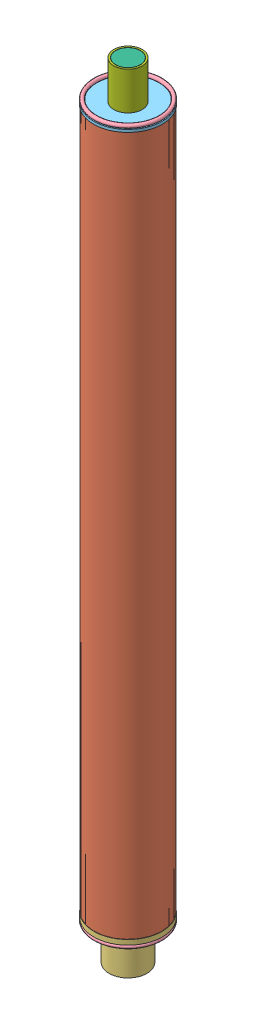
SolidWorks assembly N2000W_Reload_Assembeled, configuration Default. Lengths in mm.
Overall size (129.43 1050.01 129.43).
15 component instances, 9 part files, 26 mates.
Components (placement in the parent):
- N2000W_Grain-1: N2000W_Grain [Default] at origin size (85.22 152.4 85.22)
- N2000W_Grain-2: N2000W_Grain [Default] at (0 457.2 0) x (0.999641 0 -0.02679) z (0.02679 0 0.999641) size (85.22 152.4 85.22)
- N2000W_Grain-3: N2000W_Grain [Default] at (0 152.4 0) size (85.22 152.4 85.22)
- N2000W_Grain-4: N2000W_Grain [Default] at (0 609.6 0) x (0.569996 0 0.821647) z (-0.821647 0 0.569996) size (85.22 152.4 85.22)
- N2000W_Grain-6: N2000W_Grain [Default] at (0 304.8 0) size (85.22 152.4 85.22)
- N2000W_Reload_Liner-1: N2000W_Reload_Liner [Default] at (0 -9.144 0) x (0.685714 0 0.727871) z (-0.727871 0 0.685714) size (91.16 936.62 91.16)
- N2000W_Grain-7: N2000W_Grain [Default] at (0 762 0) size (85.22 152.4 85.22)
- N2000W_Nozel-1: N2000W_Nozel [Default] at (0 -42.8244 0) x (-0.670154 0 -0.742222) z (-0.742222 0 0.670154) size (91.64 68.22 91.64)
- N2000W_O_Ring-1: N2000W_O_Ring [Default] at (0 -18.3388 0) x (-0.992176 0 0.124851) z (0.124851 0 0.992176) size (92.2 5.18 92.2)
- N2000W_O_Ring-2: N2000W_O_Ring [Default] at (0 933.577 0) x (0.982844 0 -0.18444) z (0.18444 0 0.982844) size (92.2 5.18 92.2)
- N2000W_Forward_Seal_Disc-1: N2000W_Forward_Seal_Disc [Default] at (0 930.9862 0) size (92.15 7.62 92.15)
- Part7^N2000W_Reload_Assembeled-1: Part7^N2000W_Reload_Assembeled [Default] at origin (virtual)
- Part8^N2000W_Reload_Assembeled-1: Part8^N2000W_Reload_Assembeled [Default] at origin (virtual)
- N2000W_Smoke_Grain-1: N2000W_Smoke_Grain [Default] at (0 930.9862 0) x (1 0 0) z (0 1 0) size (32.89 32.89 50.75)
- N2000W_Smoke_Grain_Liner-1: N2000W_Smoke_Grain_Liner [Default] at (0 930.9862 0) x (1 0 0) z (0 1 0) size (38.1 38.1 50.8)
Mates (geometry in assembly coordinates):
- Coincident2: coordinate: point of ?
- Parallel1: parallel anti-aligned: plane of N2000W_Grain-1 through (0 0 0) normal (0 -1 0); plane of assembly through (0 0 0) normal (0 1 0)
- Coincident3: coincident aligned: axis of N2000W_Grain-1 through (0 152.4 0) axis (0 -1 0); axis of N2000W_Grain-3 through (0 304.8 0) axis (0 -1 0)
- Coincident4: coincident aligned: axis of N2000W_Grain-2 through (0 609.6 0) axis (0 -1 0); axis of N2000W_Grain-3 through (0 304.8 0) axis (0 -1 0)
- Coincident5: coincident aligned: axis of N2000W_Grain-2 through (0 609.6 0) axis (0 -1 0); axis of N2000W_Grain-4 through (0 762 0) axis (0 -1 0)
- Coincident8: coincident aligned: axis of N2000W_Grain-1 through (0 152.4 0) axis (0 -1 0); axis of N2000W_Grain-6 through (0 457.2 0) axis (0 -1 0)
- Coincident9: coincident anti-aligned: plane of N2000W_Grain-1 through (0 152.4 0) normal (0 1 0); plane of N2000W_Grain-3 through (0 152.4 0) normal (0 -1 0)
- Coincident10: coincident anti-aligned: plane of N2000W_Grain-3 through (0 304.8 0) normal (0 1 0); plane of N2000W_Grain-6 through (0 304.8 0) normal (0 -1 0)
- Coincident11: coincident anti-aligned: plane of N2000W_Grain-2 through (0 457.2 0) normal (0 -1 0); plane of N2000W_Grain-6 through (0 457.2 0) normal (0 1 0)
- Coincident12: coincident anti-aligned: plane of N2000W_Grain-2 through (0 609.6 0) normal (0 1 0); plane of N2000W_Grain-4 through (0 609.6 0) normal (0 -1 0)
- Coincident14: coincident aligned: axis of N2000W_Grain-1 through (0 152.4 0) axis (0 -1 0); axis of N2000W_Reload_Liner-1 through (0 927.481 0) axis (0 -1 0)
- Coincident17: coincident anti-aligned: plane of N2000W_Grain-4 through (0 762 0) normal (0 1 0); plane of N2000W_Grain-7 through (0 762 0) normal (0 -1 0)
- Coincident18: coincident aligned: axis of N2000W_Reload_Liner-1 through (0 927.481 0) axis (0 -1 0); axis of N2000W_Grain-7 through (0 914.4 0) axis (0 -1 0)
- Coincident19: coincident aligned: axis of N2000W_Nozel-1 through (0 -9.144 0) axis (0 1 0); axis of N2000W_O_Ring-1 through (0 -44.438 0) axis (0 1 0)
- Tangent1: tangent: face of N2000W_O_Ring-1; plane of N2000W_Nozel-1 through (30.7075 -15.748 34.0098) normal (0 -1 0)
- Coincident23: coincident anti-aligned: axis of N2000W_Grain-1 through (0 152.4 0) axis (0 -1 0); axis of N2000W_Nozel-1 through (0 -68.2244 0) axis (0 1 0)
- Coincident24: coincident anti-aligned: axis of N2000W_O_Ring-2 through (0 959.6762 0) axis (0 -1 0); axis of N2000W_Forward_Seal_Disc-1 through (0 923.3662 0) axis (0 1 0)
- Tangent2: tangent: face of N2000W_O_Ring-2; plane of N2000W_Forward_Seal_Disc-1 through (-11.3157 930.9862 0) normal (0 1 0)
- Coincident25: coincident anti-aligned: plane of N2000W_Reload_Liner-1 through (0 927.481 0) normal (0 1 0); plane of N2000W_Forward_Seal_Disc-1 through (-46.0756 927.481 0) normal (0 -1 0)
- Coincident26: coincident aligned: axis of N2000W_Reload_Liner-1 through (0 927.481 0) axis (0 -1 0); axis of N2000W_O_Ring-2 through (0 959.6762 0) axis (0 -1 0)
- Coincident27: coincident anti-aligned: plane of N2000W_Grain-1 through (0 0 0) normal (0 -1 0); plane of N2000W_Nozel-1 through (23.4987 0 26.0258) normal (0 1 0)
- Coincident28: coincident anti-aligned: plane of N2000W_Reload_Liner-1 through (0 -9.144 0) normal (0 -1 0); plane of N2000W_Nozel-1 through (28.3599 -9.144 31.4098) normal (0 1 0)
- Coincident29: coincident aligned: axis of N2000W_Smoke_Grain-1 through (319.9374 981.7354 -288.7882) axis (0 -1 0); axis of N2000W_Smoke_Grain_Liner-1 through (319.9374 981.7862 -288.7882) axis (0 -1 0)
- Coincident30: coincident aligned: plane of N2000W_Smoke_Grain-1 through (319.9374 930.9862 -288.7882) normal (0 -1 0); plane of N2000W_Smoke_Grain_Liner-1 through (319.9374 930.9862 -288.7882) normal (0 -1 0)
- Coincident32: coincident anti-aligned: plane of N2000W_Forward_Seal_Disc-1 through (-11.3157 930.9862 0) normal (0 1 0); plane of N2000W_Smoke_Grain-1 through (0 930.9862 0) normal (0 -1 0)
- Coincident33: coincident aligned: axis of N2000W_O_Ring-2 through (0 959.6762 0) axis (0 -1 0); axis of N2000W_Smoke_Grain_Liner-1 through (0 981.7862 0) axis (0 -1 0)
